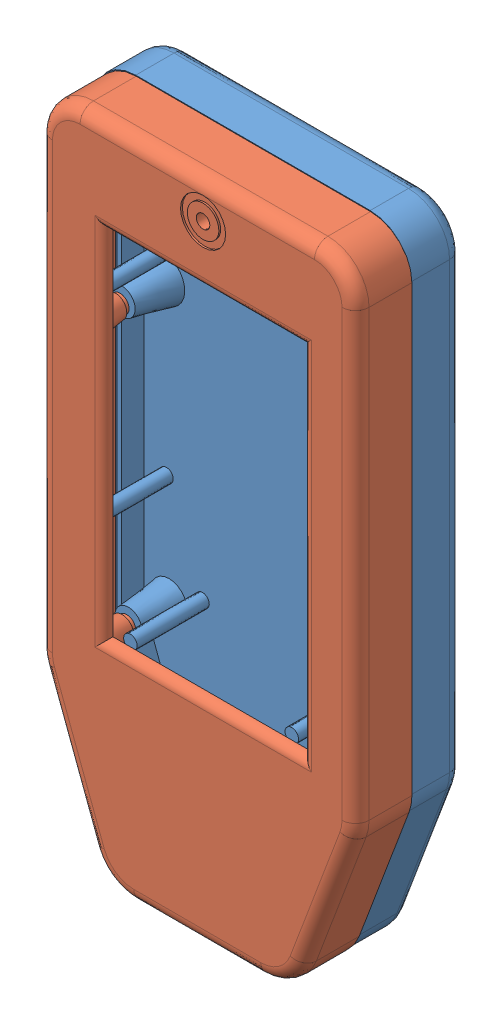
SolidWorks assembly control_ensamble, configuration Predeterminado. Lengths in mm.
Overall size (70.32 147.16 23.95).
2 component instances, 2 part files, 2 mates.
Components (placement in the parent):
- control parte inferior-1: control parte inferior [Predeterminado] at (-60.6215 -36.3767 136.5) size (70.24 147 21)
- control parte superior-1: control parte superior [Predeterminado] at (-52.8441 -36.5376 160.4502) x (-1 0 0) z (0 0 -1) size (70.24 147 14)
Mates (geometry in assembly coordinates):
- Paralelo2: parallel anti-aligned: plane of control parte inferior-1 through (-30.7774 50.4605 140) normal (0 0 1); plane of control parte superior-1 through (-70.7693 -77.5828 158.4502) normal (0 0 -1)
- Ángulo1: planar angle = 0 rad aligned: plane of control parte superior-1 through (-21.5705 50.2996 147.9502) normal (1 0 0); plane of control parte inferior-1 through (-21.6597 -48.0695 148) normal (1 0 0)
